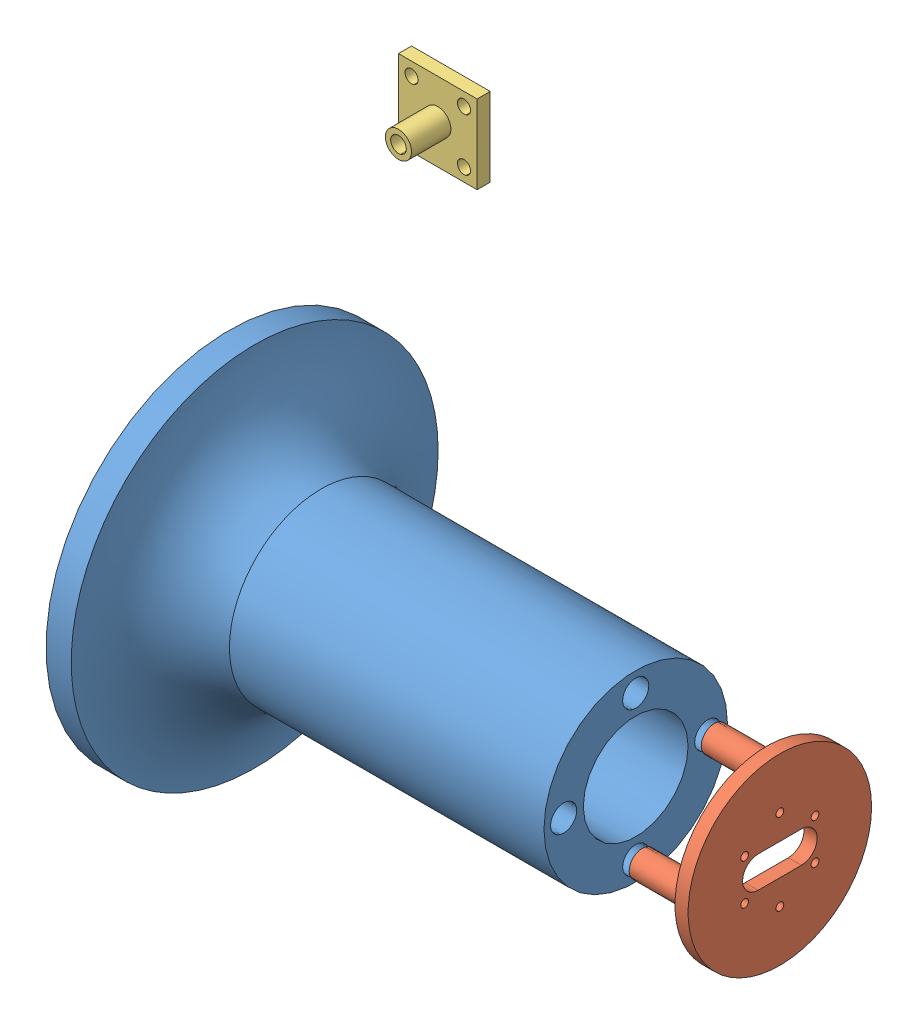
SolidWorks assembly Montagem pendulo novo, configuration Valor predeterminado. Lengths in mm.
Overall size (240.24 168.86 169.73).
3 component instances, 3 part files, 3 mates.
Components (placement in the parent):
- base nova-1: base nova [Valor predeterminado] at (-1.3263 -6.1739 0) size (155 140 140)
- tampa nova-1: tampa nova [Valor predeterminado] at (114.6636 -6.1739 0) x (0 0 1) z (-1 0 0) size (70 70 25)
- encaixe inferior-1: encaixe inferior [Valor predeterminado] at (-110.5801 77.6834 -99.726) size (30 30 20)
Mates (geometry in assembly coordinates):
- Concêntrico1: concentric anti-aligned: circle of base nova-1; circle of tampa nova-1
- Concêntrico2: concentric anti-aligned: circle of base nova-1; circle of tampa nova-1
- Distância1: distance = 50 mm anti-aligned: plane of tampa nova-1 through (109.6636 -6.1739 0) normal (-1 0 0); plane of base nova-1 through (59.6636 -6.1739 0) normal (1 0 0)
